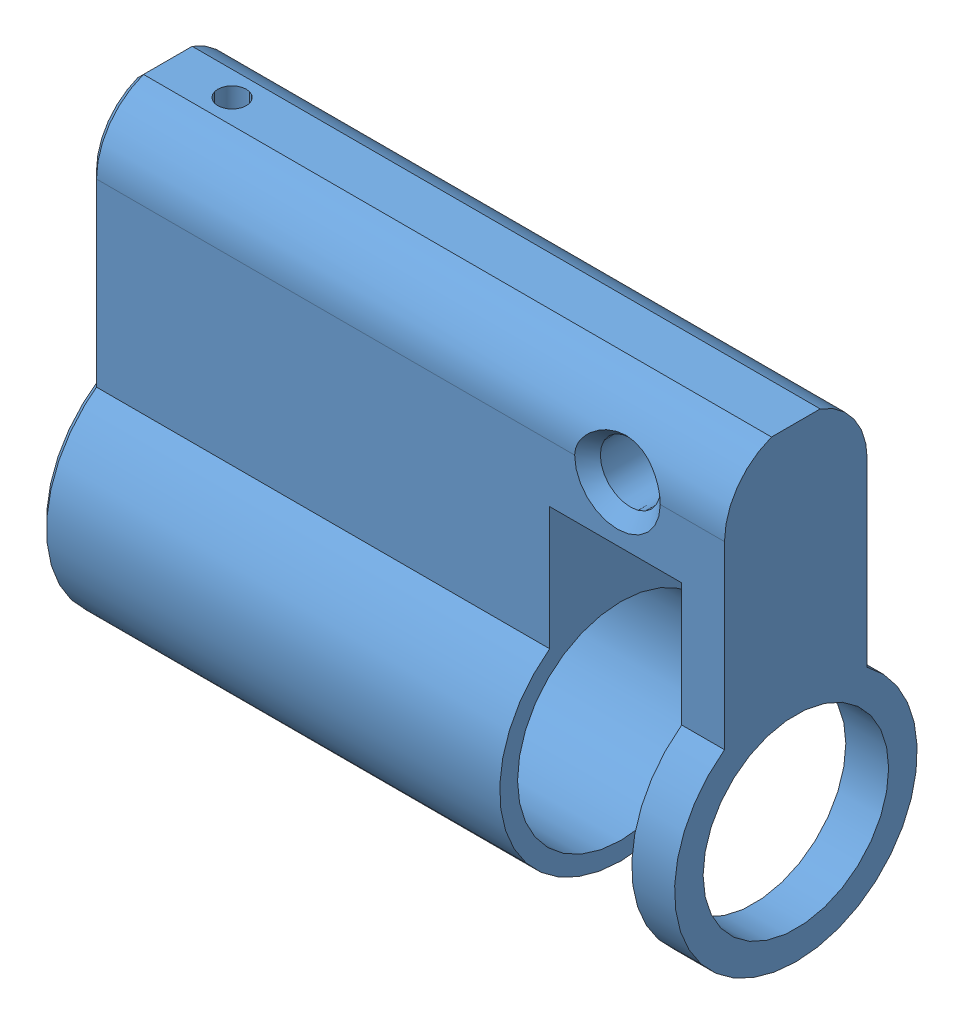
SolidWorks assembly cylinder_sub-assembly_e, configuration Default. Lengths in mm.
Overall size (44.5 32.7 17).
2 component instances, 2 part files, 1 mates.
Components (placement in the parent):
- cylinder_d-1: cylinder_d [one-pair_of_pins] at origin size (44.5 32.7 17)
- upper_half_pin_y-1: upper_half_pin_y [cut_depth_2] at (5 15.25 0) x (1 0 0) z (0 -1 0) size (2 2 8)
Mates (geometry in assembly coordinates):
- Concentric1: concentric anti-aligned: cylinder of cylinder_d-1 through (5 35 0) axis (0 -1 0) radius 1; cylinder of upper_half_pin_y-1 through (5 7.25 0) axis (0 1 0) radius 1
